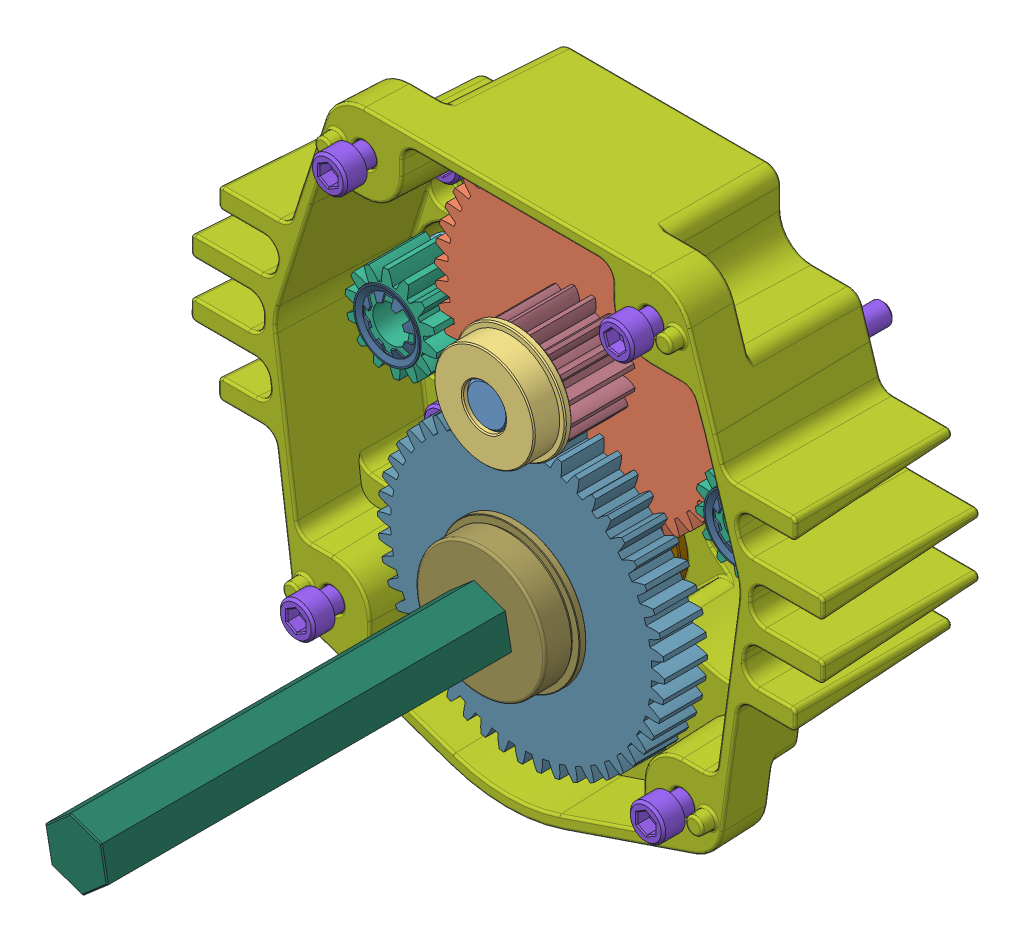
SolidWorks assembly ToughboxMini, configuration Default. Lengths in mm.
Overall size (140.05 131.62 142.29).
31 component instances, 15 part files, 0 mates.
Components (placement in the parent):
- TBMiniSmallHexShaft-1: TBMiniSmallHexShaft [Default] at (-127.8104 29.3671 -52.3959) x (-0.59657 -0.802561 0) z (-0.802561 0.59657 0) size (11 38.23 9.52)
- ToughboxLargeClusterGear_Hex_50t0.375-1: ToughboxLargeClusterGear_Hex_50t0.375 [Default] at (-91.0349 50.9043 -67.5597) x (-0.59657 -0.802561 0) z (0 0 -1) size (65.97 66.04 10.34)
- Bearing_FR6ZZ-1: Bearing_FR6ZZ [Default] at (-96.247 60.278 -52.5991) x (-0.893862 0.448342 0) z (0 0 1) size (24.69 24.69 7.16)
- NylockNut_10-32-1: NylockNut_10-32 [Default] at (-129.8464 -8.0737 -56.3837) x (0.501678 0.865055 0) z (0 0 -1) size (9.53 11 5.96)
- NylockNut_10-32-2: NylockNut_10-32 [Default] at (-59.2462 80.7349 -56.3837) x (0.999999 -0.001296 0) z (0 0 -1) size (9.53 11 5.96)
- NylockNut_10-32-3: NylockNut_10-32 [Default] at (-122.7461 80.8172 -56.3837) x (0.500567 0.865698 0) z (0 0 -1) size (9.53 11 5.96)
- NylockNut_10-32-4: NylockNut_10-32 [Default] at (-52.3764 -8.1741 -56.3837) x (-0.501678 -0.865055 0) z (0 0 -1) size (9.53 11 5.96)
- Washer_5-16-1: Washer_5-16 [Default] at (-52.3162 38.3079 -77.7705) x (0.171117 0.985251 0) z (0 0 -1) size (17.53 17.53 1.47)
- Washer_5-16-2: Washer_5-16 [Default] at (-52.3162 38.3079 -76.2973) x (0.897267 -0.441488 0) z (0 0 -1) size (17.53 17.53 1.47)
- Washer_5-16-3: Washer_5-16 [Default] at (-129.7861 38.4083 -77.7705) x (-0.990116 0.140253 0) z (0 0 1) size (17.53 17.53 1.47)
- Washer_5-16-4: Washer_5-16 [Default] at (-129.7861 38.4083 -79.2437) x (-0.681761 0.731575 0) z (0 0 1) size (17.53 17.53 1.47)
- CIMGear_14t8mm-1: CIMGear_14t8mm [Default] at (-52.3162 38.3079 -63.5973) x (-0.998626 0.052407 0) z (0 0 -1) size (20.03 20.32 12.7)
- CIMGear_14t8mm-2: CIMGear_14t8mm [Default] at (-129.7861 38.4083 -63.5973) x (-0.70887 0.705339 0) z (0 0 -1) size (20.03 20.32 12.7)
- TBMiniHousing-1: TBMiniHousing [Default] at (-91.0876 10.1882 -86.3557) x (0.999999 -0.001296 0) z (0 0 1) size (139.9 118.55 41.62)
- Screw_SHCS_10-32x0.625-1: Screw_SHCS_10-32x0.625 [Default] at (-52.2832 63.7078 -74.4685) x (-0.564778 -0.825243 0) z (-0.825243 0.564778 0) size (7.82 20.65 7.82)
- Screw_SHCS_10-32x0.625-2: Screw_SHCS_10-32x0.625 [Default] at (-122.7461 80.8172 -42.5915) x (0.507484 -0.861661 0) z (-0.861661 -0.507484 0) size (7.82 20.65 7.82)
- Screw_SHCS_10-32x0.625-3: Screw_SHCS_10-32x0.625 [Default] at (-52.3764 -8.1741 -42.5915) x (0.507484 -0.861661 0) z (-0.861661 -0.507484 0) size (7.82 20.65 7.82)
- Screw_SHCS_10-32x0.625-4: Screw_SHCS_10-32x0.625 [Default] at (-129.8464 -8.0737 -42.5915) x (0.507484 -0.861661 0) z (-0.861661 -0.507484 0) size (7.82 20.65 7.82)
- Screw_SHCS_10-32x0.625-5: Screw_SHCS_10-32x0.625 [Default] at (-59.2462 80.7349 -42.5915) x (0.740711 -0.671824 0) z (-0.671824 -0.740711 0) size (7.82 20.65 7.82)
- Screw_SHCS_10-32x0.625-6: Screw_SHCS_10-32x0.625 [Default] at (-52.3491 12.9079 -74.4685) x (-0.564778 -0.825243 0) z (-0.825243 0.564778 0) size (7.82 20.65 7.82)
- Screw_SHCS_10-32x0.625-7: Screw_SHCS_10-32x0.625 [Default] at (-129.7532 63.8083 -74.4685) x (-0.966277 -0.257503 0) z (-0.257503 0.966277 0) size (7.82 20.65 7.82)
- Screw_SHCS_10-32x0.625-8: Screw_SHCS_10-32x0.625 [Default] at (-129.819 13.0083 -74.4685) x (-0.99652 0.083357 0) z (0.083357 0.99652 0) size (7.82 20.65 7.82)
- Bearing_R6ZZ-1: Bearing_R6ZZ [Default] at (-91.0349 50.9043 -84.8317) x (0.958138 -0.286306 0) z (0 0 1) size (22.23 22.23 7.11)
- Bearing_R6ZZ-2: Bearing_R6ZZ [Default] at (-91.0876 10.1882 -84.8317) x (-0.661529 0.74992 0) z (0 0 1) size (22.23 22.23 7.11)
- RetainingClip-1: RetainingClip [Default] at (-129.7861 38.4083 -63.5973) x (0 0 1) z (-1 0 0) size (1.12 14.83 14.83)
- RetainingClip-2: RetainingClip [Default] at (-52.3162 38.3079 -63.5973) x (0 0 1) z (-1 0 0) size (1.12 14.83 14.83)
- ExternalKlipring-1: ExternalKlipring [Default] at (-91.0876 10.1882 -64.4355) x (0.996411 -0.084651 0) z (0 0 1) size (19.07 20.96 1.27)
- Bearing_Hex_FR8ZZ-1: Bearing_Hex_FR8ZZ [Default] at (-91.0876 10.1882 -44.6717) x (0.188693 -0.982036 0) z (0 0 -1) size (31.12 31.12 7.93)
- SmallClusterGear_Hex_16t0.375-1: SmallClusterGear_Hex_16t0.375 [Default] at (-91.0349 50.9043 -67.5597) x (0 0 1) z (0.396753 -0.917925 0) size (15.19 22.57 22.57)
- LargeOutputGear_Hex_48t0.5-1: LargeOutputGear_Hex_48t0.5 [Default] at (-91.0876 10.1882 -63.1655) x (0 0 1) z (0.756122 0.654431 0) size (10.21 63.42 63.42)
- TBMiniHexOutputShaft-1: TBMiniHexOutputShaft [Default] at (-100.2289 -30.5762 -52.3197) x (0.188693 -0.982036 0) z (-0.982036 -0.188693 0) size (14.66 142.29 12.7)
